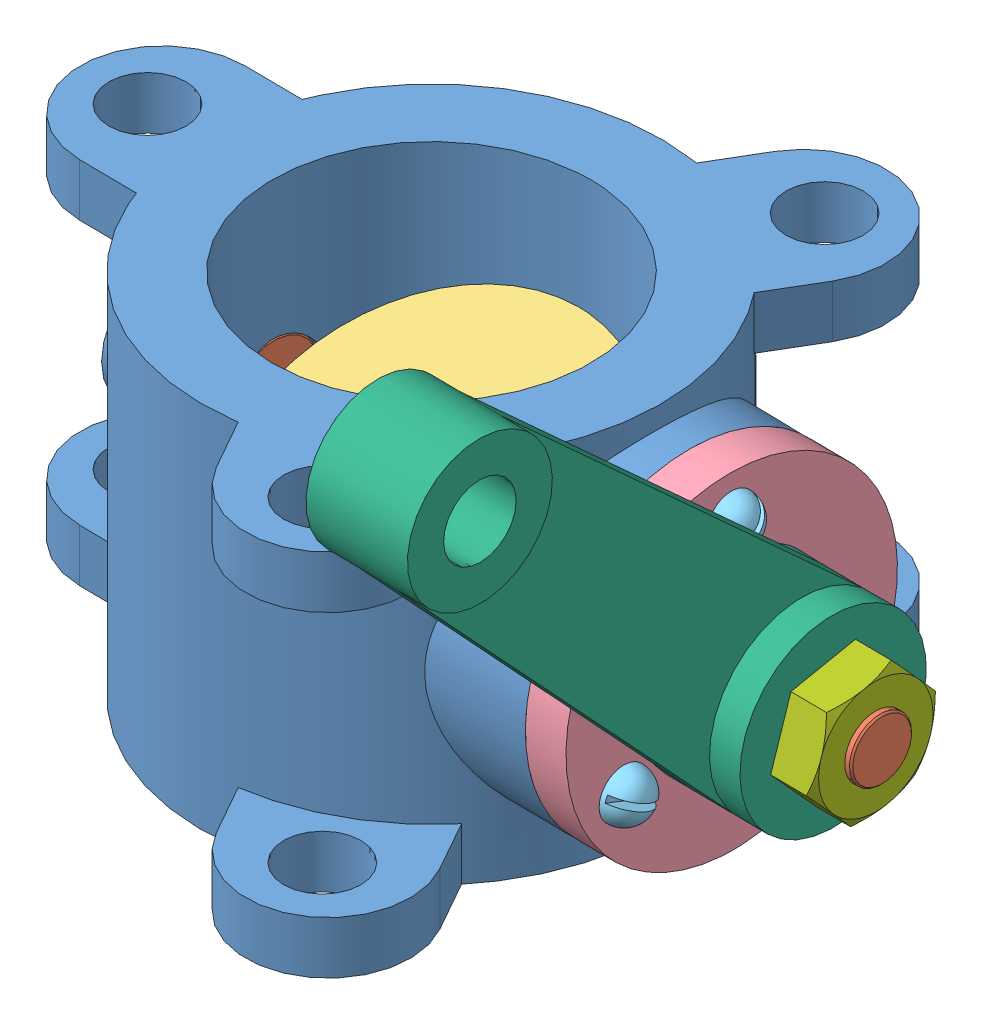
SolidWorks assembly Assem2, configuration Default. Lengths in mm.
Overall size (789.53 789.53 789.53).
9 component instances, 7 part files, 14 mates.
Components (placement in the parent):
- part7-1: part7 [Default] at (54.602 112.5 -53.5092) x (-0.999945 0 -0.010522) z (0.010522 0 -0.999945) size (375.77 225 387.12)
- Part1-3: Part1 [Default] at (332.2866 112.5 -50.5874) x (-0.999945 0 -0.010522) z (0.009517 0.426424 -0.904473) size (389.8 87.2 87.2)
- Part2-1: Part2 [Default] at (54.4997 112.2757 -53.0344) x (0.999989 0.004487 0.001005) z (0.001005 -0.426401 0.904534) size (193.8 6 205)
- Part3-1: Part3 [Default] at (214.5931 112.5 -51.8258) x (0.010522 0 -0.999945) z (0 -1 0) size (200 25 200)
- Part6-4: Part6 [Default] at (239.5917 187.5 -51.5627) x (0.006619 -0.777319 -0.629072) z (-0.008179 -0.629107 0.777276) size (30 49.87 30)
- Part6-5: Part6 [Default] at (238.9083 75 13.3856) x (0.003773 0.933482 -0.358604) z (0.009822 -0.358624 -0.93343) size (30 49.87 30)
- Part6-6: Part6 [Default] at (240.2751 75 -116.511) x (-0.010392 -0.156163 0.987677) z (-0.001643 0.987731 0.156155) size (30 49.87 30)
- Part5-1: Part5 [Default] at (270.84 112.5 -51.2339) x (-0.007475 0.703741 0.710417) z (0.007404 0.710457 -0.703702) size (400 62.5 112.5)
- Part4-1: Part4 [Default] at (303.3882 112.5 -50.8915) x (-0.003231 -0.951696 0.307024) z (-0.010013 0.307041 0.951644) size (79.67 25 69)
Mates (geometry in assembly coordinates):
- Coincident1: coincident anti-aligned: plane of part7-1 through (54.602 0 -53.5092) normal (0 -1 0); plane of assembly through (0 0 0) normal (0 1 0)
- Concentric1: concentric: cylinder of part7-1 through (-95.3897 112.5 -55.0875) axis (0.999945 0 0.010522) radius 28.1; cylinder of Part1-3 through (360.3996 112.5 -50.2916) axis (0.999945 0 0.010522) radius 28
- Coincident7: coincident: plane of part7-1 through (189.5945 112.5 -52.0888) normal (0.999945 0 0.010522); plane of Part1-3 through (189.333 76.6802 -27.2326) normal (-0.999945 0 -0.010522)
- Coincident8: coincident: circle of Part1-3; circle of Part2-1
- Coincident9: coincident: circle of part7-1; circle of Part3-1
- Concentric2: concentric: circle of part7-1; circle of Part3-1
- Concentric4: concentric: cylinder of Part3-1 through (164.5959 187.5 -52.3518) axis (0.999945 0 0.010522) radius 10.15; cylinder of Part6-4 through (268.174 187.5 -51.262) axis (0.999945 0 0.010522) radius 10
- Coincident15: coincident: plane of Part3-1 through (239.5917 112.5 -51.5627) normal (0.999945 0 0.010522); plane of Part6-4 through (239.6579 179.7268 -57.8535) normal (-0.999945 0 -0.010522)
- Concentric5: concentric: cylinder of Part1-3 through (332.2866 112.5 -50.5874) axis (0.999945 0 0.010522) radius 18.75; cylinder of Part5-1 through (302.0883 112.5 -50.9051) axis (-0.999945 0 -0.010522) radius 28.15
- Coincident17: coincident: plane of Part3-1 through (239.5917 112.5 -51.5627) normal (0.999945 0 0.010522); plane of Part5-1 through (239.5917 112.5 -51.5627) normal (-0.999945 0 -0.010522)
- Lock1: lock: unknown of ?; unknown of ?
- Concentric7: concentric: cylinder of Part1-3 through (332.2866 112.5 -50.5874) axis (0.999945 0 0.010522) radius 18.75; cylinder of Part4-1 through (328.3868 112.5 -50.6284) axis (-0.999945 0 -0.010522) radius 18.75
- Coincident20: coincident: plane of Part1-3 through (303.2757 97.0958 -40.2021) normal (0.999945 0 0.010522); plane of Part4-1 through (303.5169 150.4129 -63.1224) normal (-0.999945 0 -0.010522)
- Lock2: lock: unknown of ?; unknown of ?
